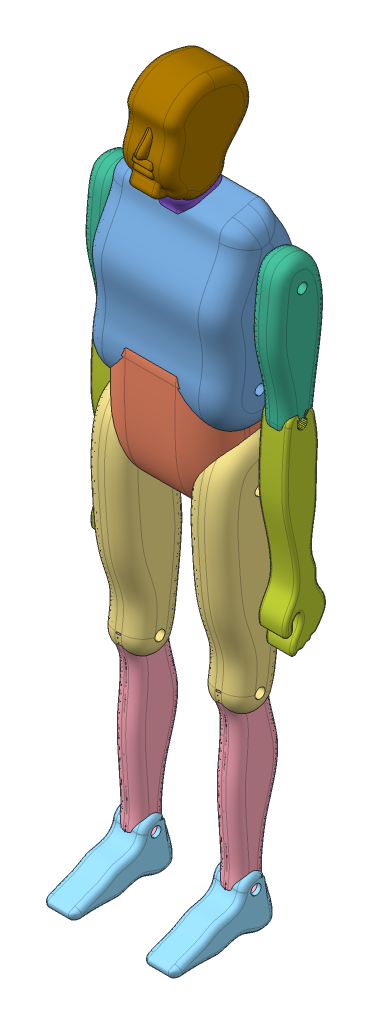
SolidWorks assembly Human_3D(10-04-12), configuration Default. Lengths in mm.
Overall size (530.68 1832.11 366.32).
14 component instances, 9 part files, 22 mates.
Components (placement in the parent):
- Chest_3D-1: Chest_3D [Default] at (-194.0697 -37.8635 128.1318) size (350.02 515.24 294.39)
- Abdominal_3D-1: Abdominal_3D [Default] at (-147.423 -255.9077 128.1318) size (309.81 426.95 250.71)
- Thigh_3D-1: Thigh_3D [Default] at (76.9303 -255.9077 128.1318) size (116.78 669.36 281.34)
- Thigh_3D-2: Thigh_3D [Default] at (-173.0697 -255.9077 128.1318) size (116.78 669.36 281.34)
- Leg_3D-1: Leg_3D [Default] at (-124.0697 -1124.992 128.1318) size (61.6 568.33 179.47)
- Leg_3D-2: Leg_3D [Default] at (125.9303 -1124.992 128.1318) size (61.6 568.33 179.47)
- Foot_3D-1: Foot_3D [Default] at (86.9303 -1224.992 128.1318) size (197.99 220.93 341.64)
- Foot_3D-2: Foot_3D [Default] at (-163.0697 -1224.992 128.1318) size (197.99 220.93 341.64)
- Arm_3D-1: Arm_3D [Default] at (176.9303 198.5522 92.8395) x (1 0 0) z (0 -0.000393 1) size (72.82 416.89 169.99)
- Arm_3D-2: Arm_3D [Default] at (-243.0697 198.5522 92.8395) size (72.82 416.89 169.99)
- Forearm_3D-1: Forearm_3D [Default] at (176.9303 -94.4478 92.7245) size (110.68 534.6 163.59)
- Forearm_3D-2: Forearm_3D [Default] at (-243.0697 -94.4478 92.8395) size (110.68 534.6 163.59)
- Neck_3D-1: Neck_3D [Default] at (-74.0697 -36.5687 126.8916) size (100.02 122.55 125.42)
- Head_3D-1: Head_3D [Default] at (-89.0697 -36.6117 126.566) size (130.02 274.22 242.86)
Mates (geometry in assembly coordinates):
- Concentric1: concentric aligned: cylinder of Chest_3D-1 through (-594.5697 -37.8635 128.1318) axis (1 0 0) radius 12.5; cylinder of Abdominal_3D-1 through (152.077 -37.8635 128.1318) axis (1 0 0) radius 12.5
- Concentric2: concentric aligned: cylinder of Abdominal_3D-1 through (152.077 -255.9077 128.1318) axis (1 0 0) radius 12.5; cylinder of Thigh_3D-1 through (176.4303 -255.9077 128.1318) axis (1 0 0) radius 12.5
- Concentric3: concentric aligned: cylinder of Abdominal_3D-1 through (152.077 -255.9077 128.1318) axis (1 0 0) radius 12.5; cylinder of Thigh_3D-2 through (-73.5697 -255.9077 128.1318) axis (1 0 0) radius 12.5
- Concentric4: concentric anti-aligned: cylinder of Thigh_3D-2 through (-73.5697 -694.992 128.1318) axis (1 0 0) radius 12.5; cylinder of Leg_3D-1 through (-83.5697 -694.992 128.1318) axis (-1 0 0) radius 12.5
- Concentric5: concentric anti-aligned: cylinder of Thigh_3D-1 through (176.4303 -694.992 128.1318) axis (1 0 0) radius 12.5; cylinder of Leg_3D-2 through (166.4303 -694.992 128.1318) axis (-1 0 0) radius 12.5
- Concentric6: concentric aligned: cylinder of Leg_3D-1 through (-83.5697 -1124.992 128.1318) axis (-1 0 0) radius 12.5; cylinder of Foot_3D-2 through (-163.5697 -1124.992 128.1318) axis (-1 0 0) radius 12.5
- Concentric7: concentric aligned: cylinder of Leg_3D-2 through (166.4303 -1124.992 128.1318) axis (-1 0 0) radius 12.5; cylinder of Foot_3D-1 through (86.4303 -1124.992 128.1318) axis (-1 0 0) radius 12.5
- Concentric8: concentric anti-aligned: cylinder of Chest_3D-1 through (-594.5697 198.5522 92.8395) axis (1 0 0) radius 12.5; cylinder of Arm_3D-1 through (176.4303 198.5522 92.8395) axis (-1 0 0) radius 12.5
- Concentric9: concentric anti-aligned: cylinder of Chest_3D-1 through (-594.5697 198.5522 92.8395) axis (1 0 0) radius 12.5; cylinder of Arm_3D-2 through (-243.5697 198.5522 92.8395) axis (-1 0 0) radius 12.5
- Concentric10: concentric anti-aligned: cylinder of Arm_3D-1 through (176.4303 -94.4478 92.7245) axis (-1 0 0) radius 12.5; cylinder of Forearm_3D-1 through (246.4303 -94.4478 92.7245) axis (1 0 0) radius 12.5
- Concentric11: concentric anti-aligned: cylinder of Arm_3D-2 through (-243.5697 -94.4478 92.8395) axis (-1 0 0) radius 12.5; cylinder of Forearm_3D-2 through (-173.5697 -94.4478 92.8395) axis (1 0 0) radius 12.5
- Coincident1: coincident anti-aligned: plane of Chest_3D-1 through (-173.5697 197.4622 10.7235) normal (-1 0 0); plane of Arm_3D-2 through (-173.5697 264.0623 93.3944) normal (1 0 0)
- Coincident2: coincident aligned: plane of Arm_3D-2 through (-243.5697 264.0623 93.3944) normal (-1 0 0); plane of Forearm_3D-2 through (-243.5697 -565.1433 60.2755) normal (-1 0 0)
- Coincident3: coincident anti-aligned: plane of Chest_3D-1 through (176.4303 197.4622 10.7235) normal (1 0 0); plane of Arm_3D-1 through (176.4303 264.0621 93.4202) normal (-1 0 0)
- Coincident4: coincident aligned: plane of Arm_3D-1 through (246.4303 264.0621 93.4202) normal (1 0 0); plane of Forearm_3D-1 through (246.4303 -565.1433 60.1604) normal (1 0 0)
- Coincident5: coincident aligned: plane of Chest_3D-1 through (176.4303 197.4622 10.7235) normal (1 0 0); plane of Thigh_3D-1 through (176.4303 -144.9178 116.849) normal (1 0 0)
- Coincident6: coincident aligned: plane of Chest_3D-1 through (-173.5697 197.4622 10.7235) normal (-1 0 0); plane of Thigh_3D-2 through (-173.5697 -144.9178 116.849) normal (-1 0 0)
- Distance1: distance = 10 mm aligned: plane of Leg_3D-2 through (156.4303 -871.8007 50.0217) normal (1 0 0); plane of Foot_3D-1 through (166.4303 -1223.7623 263.3048) normal (1 0 0)
- Distance2: distance = 10 mm aligned: plane of Foot_3D-2 through (-163.5697 -1223.7623 263.3048) normal (-1 0 0); plane of Leg_3D-1 through (-153.5697 -871.8007 50.0217) normal (-1 0 0)
- Distance3: distance = 20 mm aligned: plane of Leg_3D-2 through (156.4303 -871.8007 50.0217) normal (1 0 0); plane of Thigh_3D-1 through (176.4303 -144.9178 116.849) normal (1 0 0)
- Distance4: distance = 20 mm aligned: plane of Thigh_3D-2 through (-173.5697 -144.9178 116.849) normal (-1 0 0); plane of Leg_3D-1 through (-153.5697 -871.8007 50.0217) normal (-1 0 0)
- Distance7: distance = 115 mm aligned: plane of Head_3D-1 through (61.4303 558.6544 197.95) normal (1 0 0); plane of Chest_3D-1 through (176.4303 197.4622 10.7235) normal (1 0 0)
